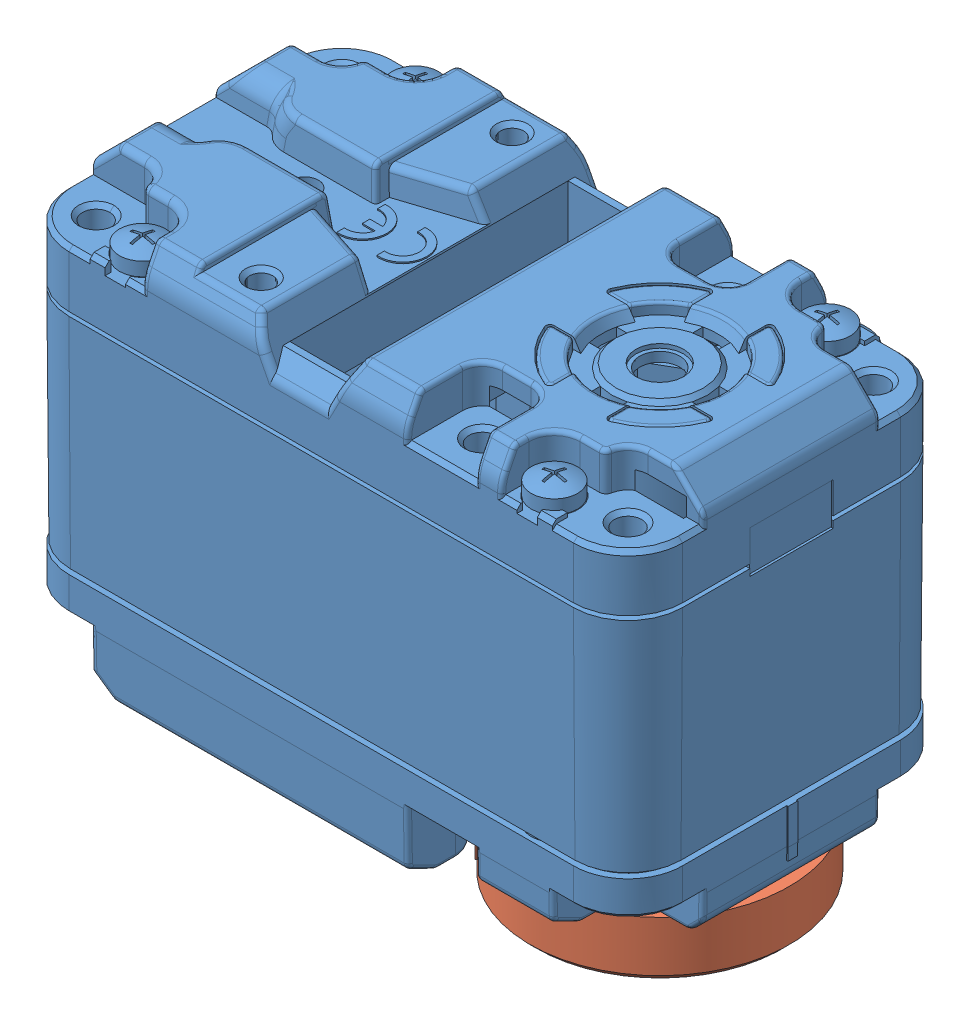
SolidWorks assembly Herkulex Assem, configuration Default. Lengths in mm.
Overall size (45.29 35.02 24.91).
2 component instances, 2 part files, 2 mates.
Components (placement in the parent):
- Herkulex-1: Herkulex [Default] at (-3.5446 3.597 -11.0386) size (45.29 35.02 24.91)
- Herkulex horn-1: Herkulex horn [Default] at (41.9148 3.997 -28.356) x (-0.746547 0 0.665333) z (-0.665333 0 -0.746547) size (19.1 6.4 19)
Mates (geometry in assembly coordinates):
- Concentric1: concentric anti-aligned: cylinder of Herkulex-1 through (22.4836 -6.003 -11.0386) axis (0 1 0) radius 1.25; cylinder of Herkulex horn-1 through (22.4836 -6.603 -11.0386) axis (0 -1 0) radius 3.25
- Coincident1: coincident anti-aligned: plane of Herkulex-1 through (32.1554 -2.403 0.9614) normal (0 -1 0); plane of Herkulex horn-1 through (22.4836 -2.403 -11.0386) normal (0 1 0)
